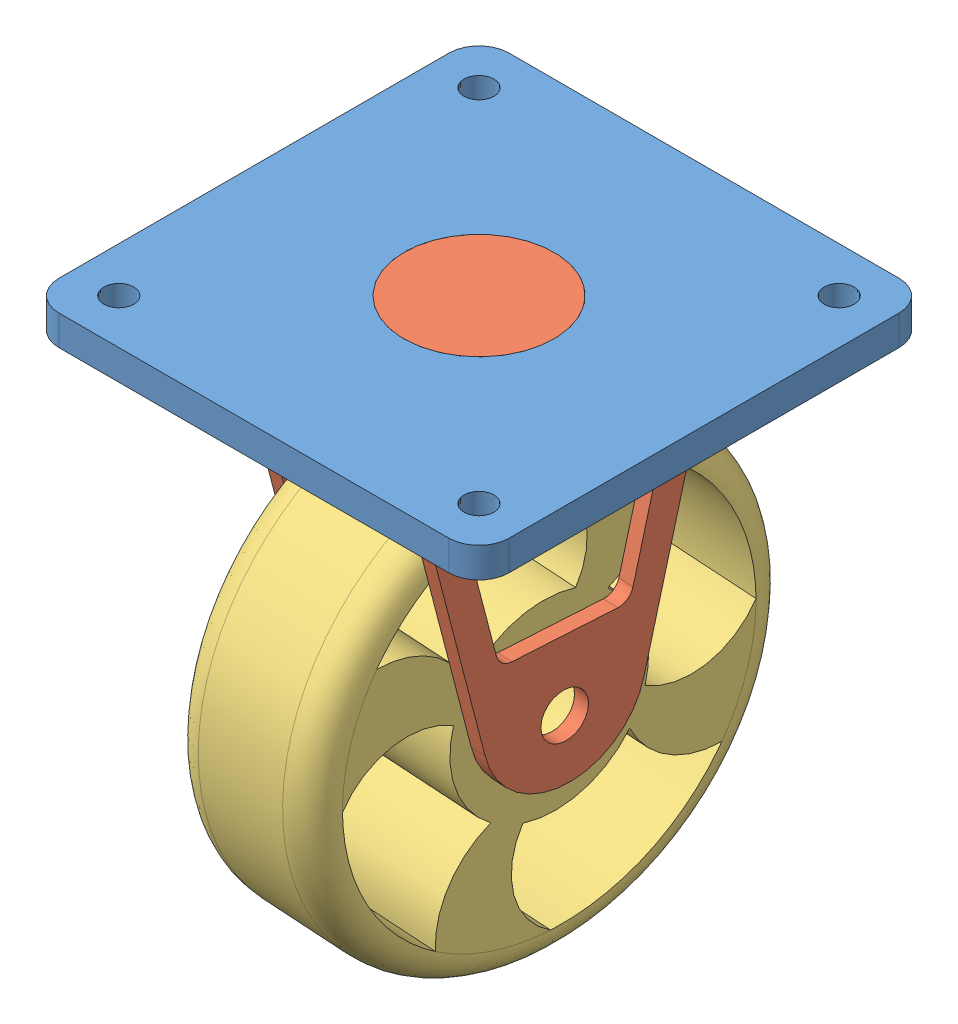
SolidWorks assembly Assem1, configuration Default. Lengths in mm.
Overall size (76.2 100.21 95.12).
8 component instances, 4 part files, 3 mates.
Components (placement in the parent):
- Part1-1: Part1 [Default] at (64.8109 45.9775 33.3533) size (76.2 5.08 76.2)
- Part2-1: Part2 [Default] at (64.8109 38.3575 33.3533) x (-0.998094 0 -0.06171) z (0.06171 0 -0.998094) size (30.99 63.5 50.8)
- Part3-1: Part3 [Default] at (52.1351 -2.2825 32.5696) x (0.998094 0 0.06171) z (0.059483 -0.266209 -0.962078) size (25.4 76.2 76.2)
- Part5-1: Part5 [Default] at (65.2258 -8.5737 26.6431) size (6.35 6.35 6.35)
- Part5-2: Part5 [Default] at (65.3084 2.1674 25.3079) x (0.997369 0.05869 0.042559) z (0.042559 -0.949244 0.311648) size (6.35 6.35 6.35)
- Part5-3: Part5 [Default] at (64.7035 6.7588 35.0912) x (0.993111 0.036272 0.111421) z (0.111421 -0.586665 -0.802128) size (6.35 6.35 6.35)
- Part5-4: Part5 [Default] at (64.2471 -1.1445 42.4728) x (0.993111 -0.036272 0.111421) z (0.111421 0.586665 -0.802128) size (6.35 6.35 6.35)
- Part5-5: Part5 [Default] at (64.5699 -10.6206 37.2516) x (0.997369 -0.05869 0.042559) z (0.042559 0.949244 0.311648) size (6.35 6.35 6.35)
Mates (geometry in assembly coordinates):
- Coincident1: coincident aligned: plane of Part1-1 through (31.7909 51.0575 66.3733) normal (0 1 0); plane of Part2-1 through (64.8109 51.0575 33.3533) normal (0 1 0)
- Concentric1: concentric aligned: cylinder of Part1-1 through (64.8109 51.0575 33.3533) axis (0 -1 0) radius 10.16; cylinder of Part2-1 through (64.8109 45.9775 33.3533) axis (0 -1 0) radius 12.7
- Concentric4: concentric anti-aligned: circle of Part2-1; circle of Part3-1
